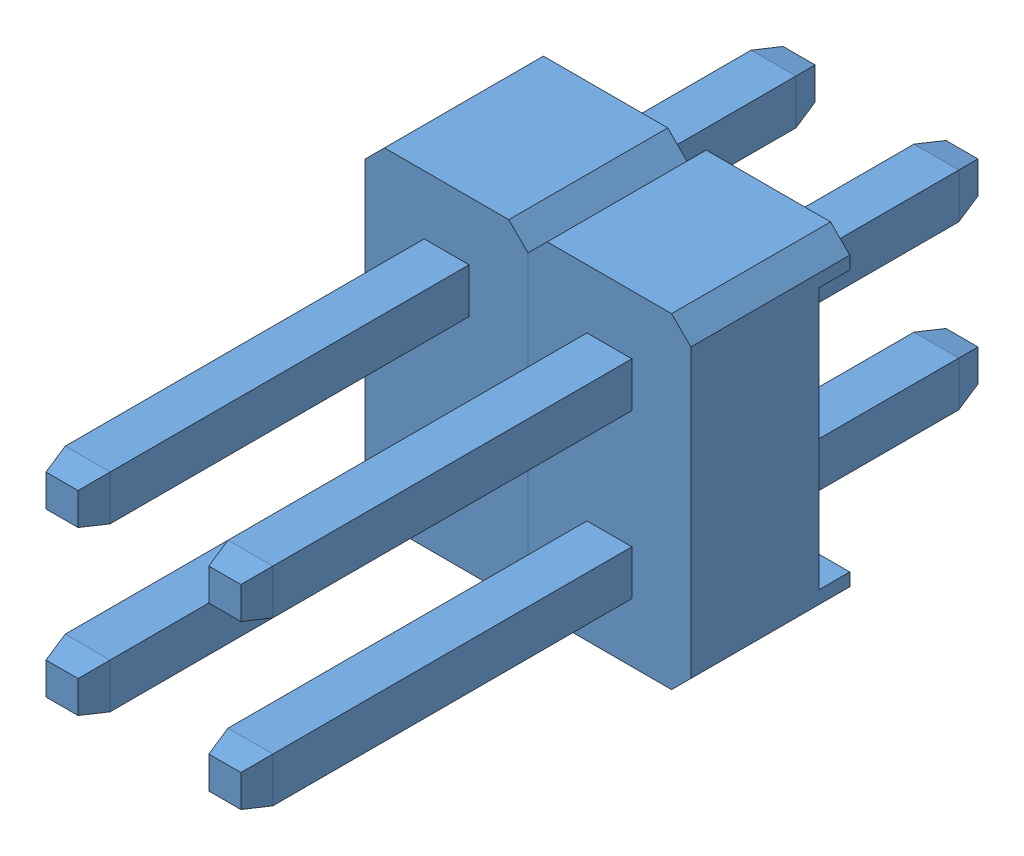
SolidWorks assembly 2x2排针, configuration 默认. Lengths in mm.
Overall size (5.08 5.08 11.5).
4 component instances, 1 part files, 0 mates.
Components (placement in the parent):
- HDR2.54-1x2P-1: HDR2.54-1x2P [默认] at (79.121 82.042 0) x (-1 0 0) z (0 0 1) size (2.54 5.08 11.5)
  - HDR2.54-1x2P-1: HDR2.54-1x2P [默认] at origin size (2.54 5.08 11.5)
- HDR2.54-1x2P-2: HDR2.54-1x2P [默认] at (81.661 82.042 0) x (-1 0 0) z (0 0 1) size (2.54 5.08 11.5)
  - HDR2.54-1x2P-1: HDR2.54-1x2P [默认] at origin size (2.54 5.08 11.5)
